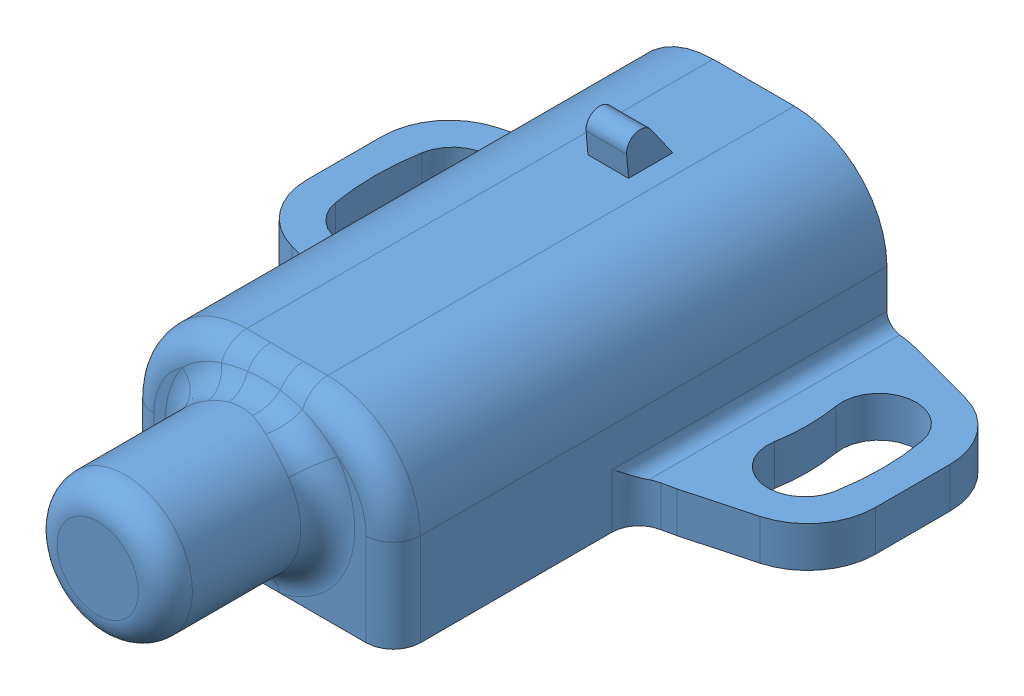
SolidWorks assembly 29103, configuration Default. Lengths in mm.
Overall size (42 16.4 48.5).
4 component instances, 3 part files, 9 mates.
Components (placement in the parent):
- 29103 Hus for føler-1: 29103 Hus for føler [Default] at origin size (42 16.4 48.5)
- 29103 Stik RS_314_1312-1: 29103 Stik RS_314_1312 [Default] at (3 -0.4 9.6) x (-1 0 0) z (0 0 -1) size (3.45 3 22.7)
- 29103 Stik RS_314_1312-2: 29103 Stik RS_314_1312 [Default] at (-3 -0.4 9.6) x (-1 0 0) z (0 0 -1) size (3.45 3 22.7)
- 29103 Tiltswitch RS_235_7623-1: 29103 Tiltswitch RS_235_7623 [Lange ben] at (0 -0.4 46.4458) x (0 0 1) z (0 -1 0) size (20.85 7.91 4.7)
Mates (geometry in assembly coordinates):
- Coincident5: coincident anti-aligned: plane of 29103 Stik RS_314_1312-1 through (4.15 0.35 25.6) normal (0 0 1); plane of 29103 Tiltswitch RS_235_7623-1 through (3 -0.4 25.6) normal (0 0 -1)
- Coincident6: coincident: line of 29103 Stik RS_314_1312-1; axis of 29103 Tiltswitch RS_235_7623-1 through (3 -0.4 30.1486) axis (0 0 -1)
- Coincident7: coincident anti-aligned: plane of 29103 Stik RS_314_1312-1 through (3 -0.4 9.6) normal (0 1 0); plane of 29103 Tiltswitch RS_235_7623-1 through (0 -0.4 46.4458) normal (0 -1 0)
- Coincident8: coincident anti-aligned: plane of 29103 Stik RS_314_1312-2 through (-1.85 0.35 25.6) normal (0 0 1); plane of 29103 Tiltswitch RS_235_7623-1 through (-3 -0.4 25.6) normal (0 0 -1)
- Coincident9: coincident aligned: plane of 29103 Stik RS_314_1312-1 through (3 -0.4 9.6) normal (0 1 0); plane of 29103 Stik RS_314_1312-2 through (-3 -0.4 9.6) normal (0 1 0)
- Distance1: distance = 6 mm aligned: plane of 29103 Stik RS_314_1312-1 through (3 -0.4 9.6) normal (-1 0 0); plane of 29103 Stik RS_314_1312-2 through (-3 -0.4 9.6) normal (-1 0 0)
- Coincident12: coincident anti-aligned: plane of 29103 Tiltswitch RS_235_7623-1 through (0 -0.4 46.4458) normal (-1 0 0); plane of assembly through (0 0 0) normal (1 0 0)
- Distance2: distance = 9.6 mm aligned: plane of 29103 Hus for føler-1 through (-3 0 0) normal (0 0 -1); plane of 29103 Stik RS_314_1312-1 through (3.65 -0.07 9.6) normal (0 0 -1)
- Distance4: distance = 0.4 mm aligned: plane of 29103 Stik RS_314_1312-1 through (3 -0.4 9.6) normal (0 1 0); plane of assembly through (0 0 0) normal (0 1 0)
